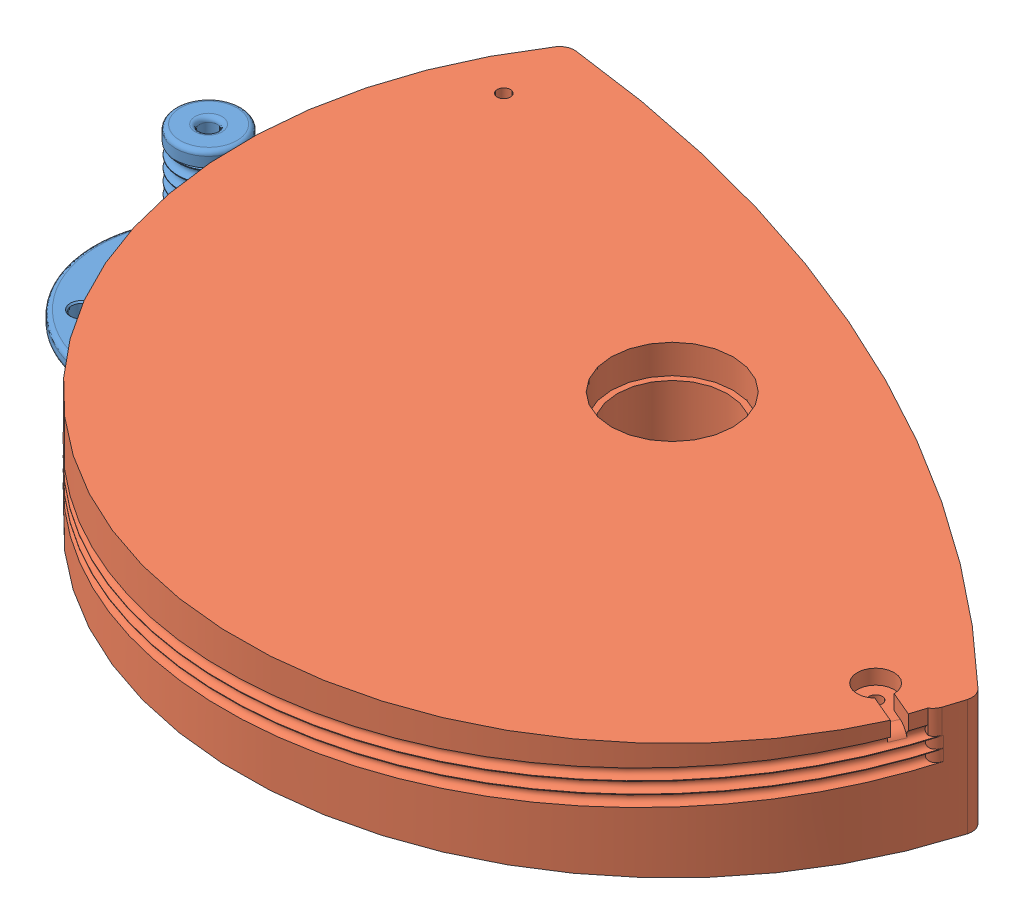
SolidWorks assembly rollers together, configuration Default. Lengths in mm.
Overall size (171.33 30.27 117.86).
2 component instances, 2 part files, 5 mates.
Components (placement in the parent):
- small roller-1: small roller [Default] at origin size (39.69 30.26 39.69)
- big roller-1: big roller [Default] at (79.9783 0 0) x (0 0 1) z (-1 0 0) size (117.86 20.11 146.73)
Mates (geometry in assembly coordinates):
- Distance1: distance = 55.5625 mm: point of small roller-1; point of big roller-1
- Coincident3: coincident aligned: plane of big roller-1 through (79.9783 0 0) normal (0 1 0)
- Coincident4: coincident: unknown of big roller-1
- Parallel2: parallel anti-aligned: plane of big roller-1 through (79.9783 0 0) normal (-1 0 0)
- Tangent1: tangent anti-aligned: cylinder of small roller-1 through (0 10.04 0) axis (0 -1 0) radius 5.6833; cylinder of big roller-1 through (79.9783 7.5 0) axis (0 -1 0) radius 74.295
